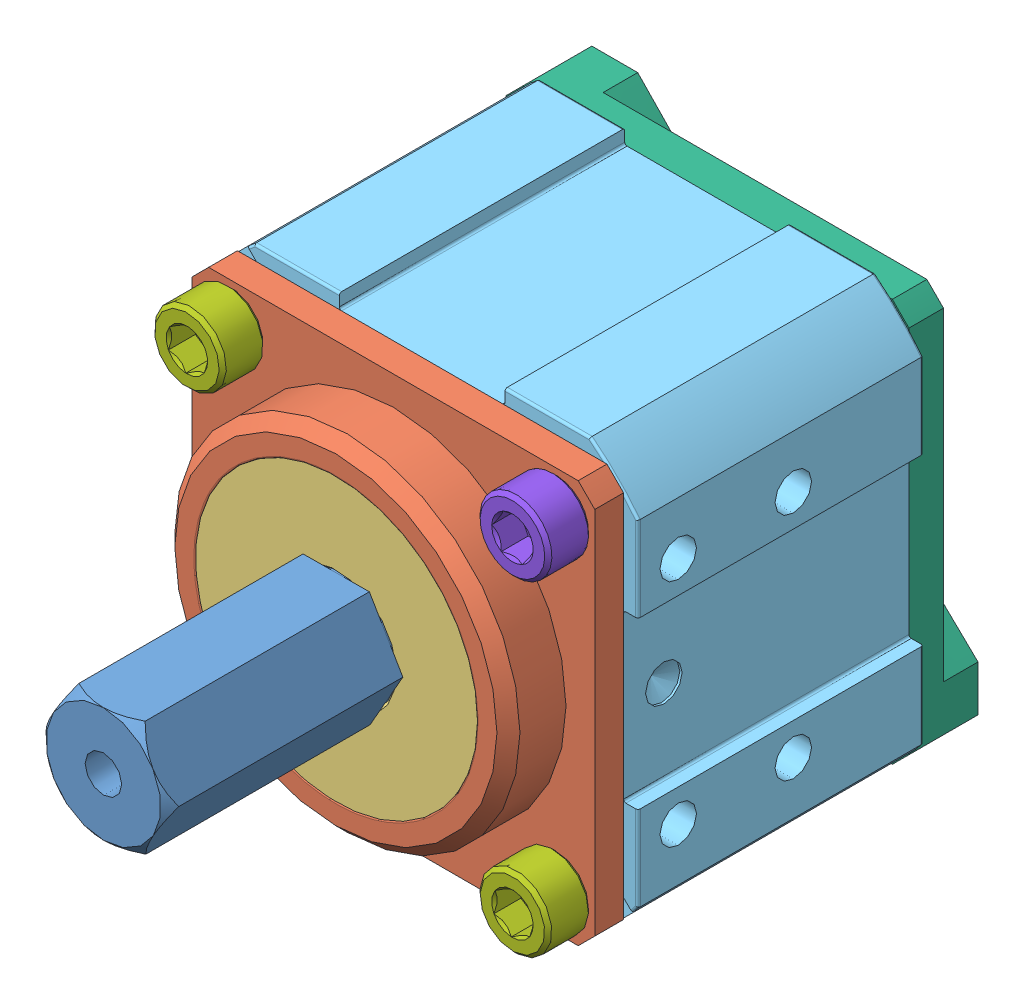
SolidWorks assembly am-3658+-+4_1+-+57+Sport, configuration Default. Lengths in mm.
Overall size (47.68 47.68 76.45).
19 component instances, 11 part files, 0 mates.
Components (placement in the parent):
- am-XXXX - 57 Sport 500 Hex Output Plug-1: am-XXXX - 57 Sport 500 Hex Output Plug [Default] at (0 0 18.923) size (44.45 44.45 56.9)
  - am-XXXX - 57 Sport 500 Hex Shaft-1: am-XXXX - 57 Sport 500 Hex Shaft [Default] at (0 0 6.2738) x (0.999982 0.006056 0) z (0 0 1) size (16.1 12.67 56.9)
  - Output Block-1: Output Block [Default] at origin size (44.45 44.45 20.32)
  - FR8ZZ Bearing-1: FR8ZZ Bearing [Default] at (8.9053 -5.9773 -13.8938) x (0.999973 0.007281 0) z (0 0 1) size (31.75 31.75 7.95)
  - FR8ZZ Bearing-2: FR8ZZ Bearing [Default] at (5.8713 8.9755 6.2738) x (0.923728 0.383049 0) z (0 0 -1) size (31.75 31.75 7.95)
  - retaining Ring 0500 - Mcm 98410A122_98410A122-1: retaining Ring 0500 - Mcm 98410A122_98410A122 [Default] at (0 0 -14.3891) x (0 0 1) z (-0.999848 0.017452 0) size (0.89 16.1 14.34)
- am-XXXX - 57 Sport 1 Stage Ring Gear Housing-1: am-XXXX - 57 Sport 1 Stage Ring Gear Housing [Default] at origin size (47.68 47.68 31.52)
- am-3765 - 57 Sport Motor Block-1: am-3765 - 57 Sport Motor Block [Default] at (0 0 -19.558) x (0 1 0) z (0 0 1) size (45.76 47.07 8.89)
- 10-32 x 1.750 SHCS_90128A953-1: 10-32 x 1.750 SHCS_90128A953 [Default] at (-17.9605 17.9605 -25.527) x (0.998431 -0.056 0) z (0 0 -1) size (7.92 7.92 49.5)
- 10-32 x 1.750 SHCS_90128A953-2: 10-32 x 1.750 SHCS_90128A953 [Default] at (17.9605 -17.9605 -25.527) x (-0.998431 0.056 0) z (0 0 -1) size (7.92 7.92 49.5)
- 10-32 X 375 SHCS_90128A940-1: 10-32 X 375 SHCS_90128A940 [Default] at (-17.9605 -17.9605 9.398) x (0.044358 0.999016 0) z (0 0 -1) size (7.92 7.92 14.58)
- 10-32 X 375 SHCS_90128A940-2: 10-32 X 375 SHCS_90128A940 [Default] at (17.9605 17.9605 9.398) x (-0.044358 -0.999016 0) z (0 0 -1) size (7.92 7.92 14.58)
- am-XXXX - 4_1 Input Stage-1: am-XXXX - 4_1 Input Stage [Default] at (0 0 1.5748) x (-0.494746 -0.869038 0) z (0 0 -1) size (35.15 35.15 14.63)
  - am-XXXX - 57 Sport Shaft Carrier Plate-1: am-XXXX - 57 Sport Shaft Carrier Plate [Default] at origin size (31.12 31.12 14.63)
  - 16T Planet Gear-1: 16T Planet Gear [Default] at (-11.8222 1.3023 11.8494) x (0 0 -1) z (1 0 0) size (7.09 12.42 12.42)
  - 16T Planet Gear-2: 16T Planet Gear [Default] at (1.3023 11.8222 11.8494) x (0 0 -1) z (0 -1 0) size (7.09 12.42 12.42)
  - 16T Planet Gear-3: 16T Planet Gear [Default] at (11.8222 -1.3023 11.8494) x (0 0 -1) z (-1 0 0) size (7.09 12.42 12.42)
  - 16T Planet Gear-4: 16T Planet Gear [Default] at (-1.3023 -11.8222 11.8494) x (0 0 -1) z (0 1 0) size (7.09 12.42 12.42)
- Thrust washer - 775 Sport-1: Thrust washer - 775 Sport [Default] at (0 0 -14.478) x (0.890996 0.454011 0) z (0 0 1) size (31 31 1.52)
